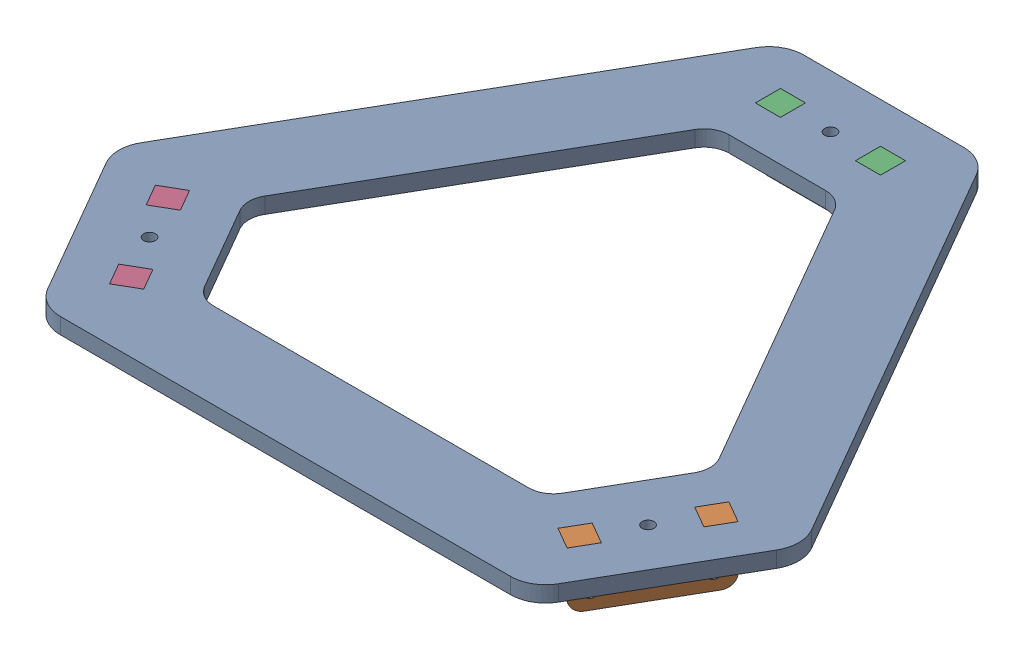
SolidWorks assembly SubASM, Modular Top, configuration Default. Lengths in mm.
Overall size (172.5 14.45 151.77).
4 component instances, 2 part files, 3 mates.
Components (placement in the parent):
- Mounting Platform-1: Mounting Platform [Default] at (-31.8491 -2.4536 29.4113) size (172.5 4.04 151.77)
- Ball Joint Housing Delrin-1: Ball Joint Housing Delrin [Default] at (34.142 -12.8676 67.5113) x (-0.5 0 0.866025) z (-0.866025 0 -0.5) size (31.75 14.45 6.35)
- Ball Joint Housing Delrin-2: Ball Joint Housing Delrin [Default] at (-31.8491 -12.8676 -46.7887) size (31.75 14.45 6.35)
- Ball Joint Housing Delrin-3: Ball Joint Housing Delrin [Default] at (-97.8402 -12.8676 67.5113) x (-0.5 0 -0.866025) z (0.866025 0 -0.5) size (31.75 14.45 6.35)
Mates (geometry in assembly coordinates):
- Coincident3: coincident anti-aligned: plane of Mounting Platform-1 through (36.5803 -2.4536 50.5882) normal (0.866025 0 0.5); plane of Ball Joint Housing Delrin-1 through (28.6428 -12.8676 64.3363) normal (-0.866025 0 -0.5)
- Coincident4: coincident anti-aligned: plane of Mounting Platform-1 through (42.0795 -2.4536 53.7632) normal (-0.5 0 0.866025); plane of Ball Joint Housing Delrin-1 through (36.5803 -12.8676 50.5882) normal (0.5 0 -0.866025)
- Coincident5: coincident aligned: plane of Mounting Platform-1 through (-31.8491 1.585 29.4113) normal (0 1 0); plane of Ball Joint Housing Delrin-1 through (20.7053 1.585 78.0845) normal (0 1 0)
